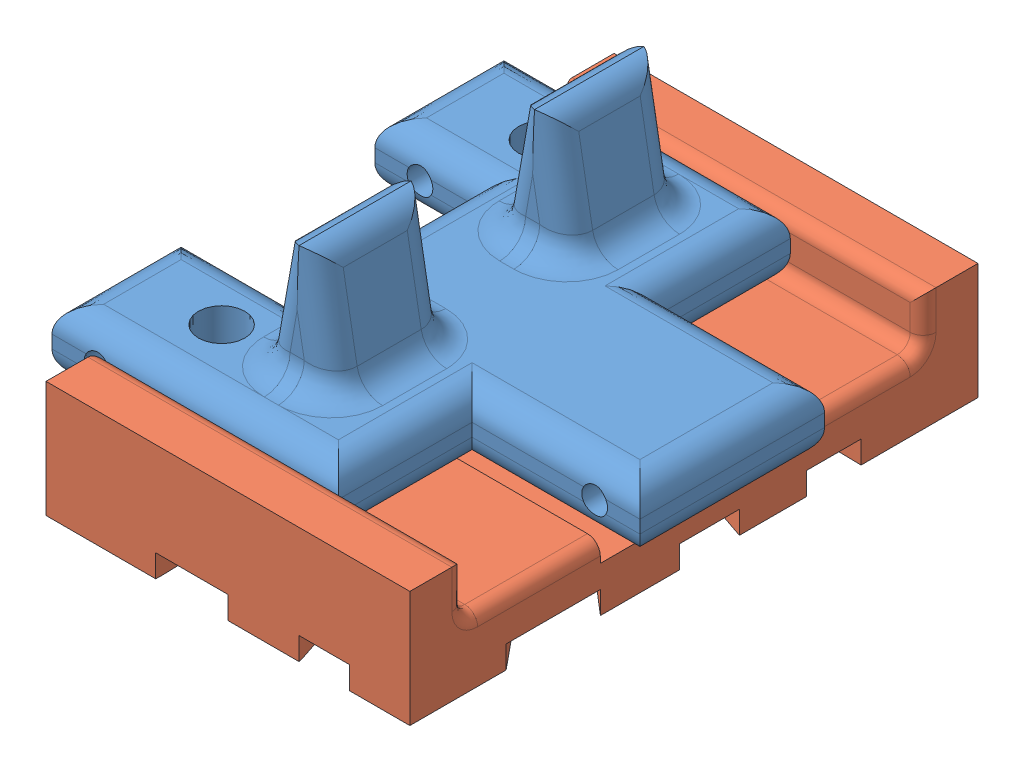
SolidWorks assembly AV_Comp_Mech_1_1_6_TrackAssembly, configuration Default. Lengths in mm.
Overall size (35.18 19.36 44).
2 component instances, 2 part files, 2 mates.
Components (placement in the parent):
- AV_Comp_Mech_1_1_3_TracksV3-1: AV_Comp_Mech_1_1_3_TracksV3 [Default] at (9.2421 14.1316 25.58) size (35.18 14.36 35)
- AV_Comp_Mech_1_1_5_OuterTrack_TPU_2-1: AV_Comp_Mech_1_1_5_OuterTrack_TPU_2 [Default] at (12.2777 11.1316 25.5805) x (1 0 0) z (0 1 0) size (28.18 44 9)
Mates (geometry in assembly coordinates):
- Coincident7: coincident aligned: circle of AV_Comp_Mech_1_1_3_TracksV3-1; circle of AV_Comp_Mech_1_1_5_OuterTrack_TPU_2-1
- Parallel4: parallel anti-aligned: plane of AV_Comp_Mech_1_1_3_TracksV3-1 through (-5.7493 19.1316 8.1805) normal (0 0 -1); plane of AV_Comp_Mech_1_1_5_OuterTrack_TPU_2-1 through (35.1877 19.1316 7.8305) normal (0 0 1)
